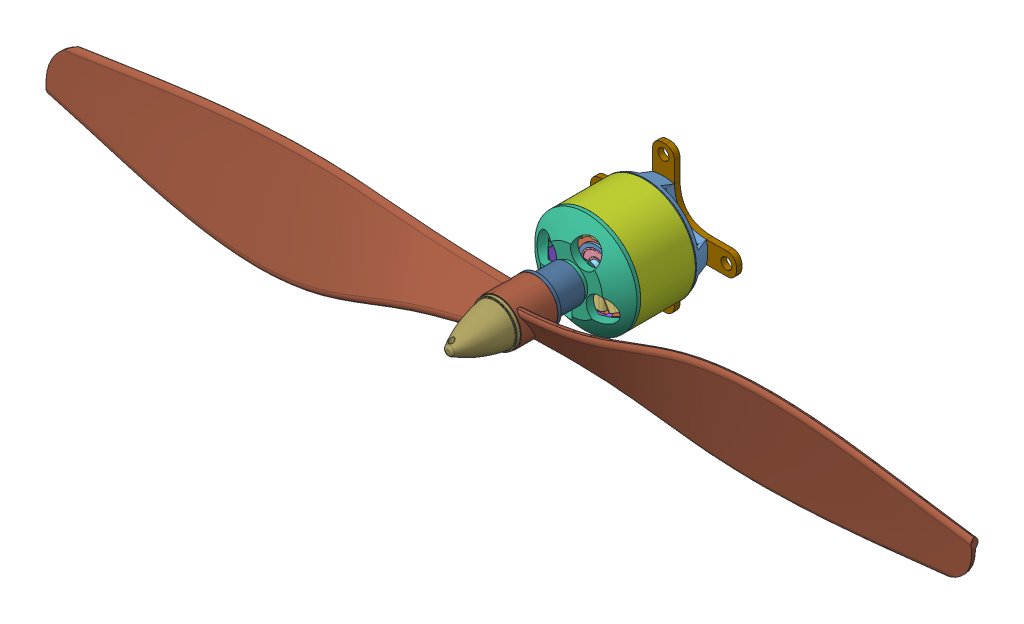
SolidWorks assembly Assem1, configuration Default. Lengths in mm.
Overall size (257.33 62.58 60.64).
40 component instances, 12 part files, 6 mates.
Components (placement in the parent):
- BLDC motor-1: BLDC motor [Default] at (-5.8676 5.6816 6.4867) size (40.24 40.24 40.73)
  - motor_stator-1: motor_stator [Default] at (4.4037 -1.9235 -1.092) size (28 28 18.85)
    - base-1: base [Default] at (10.5479 11.9817 13.9786) size (28 28 18.5)
    - armature-1: armature [Default] at (10.5479 11.9817 19.8988) x (0.999929 0.011943 0) z (0 0 1) size (22 22 12)
    - wire-1: wire [Default] at (10.4725 18.2982 25.8988) x (0.999929 0.011943 0) z (0 0 1) size (4 3.6 13.66)
    - wire-2: wire [Default] at (13.6409 17.4897 25.8988) x (0.871935 -0.489621 0) z (0 0 1) size (4 3.6 13.66)
    - wire-3: wire [Default] at (15.9805 15.2053 25.8988) x (0.510307 -0.859992 0) z (0 0 1) size (4 3.6 13.66)
    - wire-4: wire [Default] at (16.8645 12.0571 25.8988) x (0.011943 -0.999929 0) z (0 0 1) size (4 3.6 13.66)
    - wire-5: wire [Default] at (16.056 8.8887 25.8988) x (-0.489621 -0.871935 0) z (0 0 1) size (4 3.6 13.66)
    - wire-6: wire [Default] at (13.7716 6.5491 25.8988) x (-0.859992 -0.510307 0) z (0 0 1) size (4 3.6 13.66)
    - wire-7: wire [Default] at (10.6234 5.6651 25.8988) x (-0.999929 -0.011943 0) z (0 0 1) size (4 3.6 13.66)
    - wire-8: wire [Default] at (7.455 6.4736 25.8988) x (-0.871935 0.489621 0) z (0 0 1) size (4 3.6 13.66)
    - wire-9: wire [Default] at (5.1153 8.758 25.8988) x (-0.510307 0.859992 0) z (0 0 1) size (4 3.6 13.66)
    - wire-10: wire [Default] at (4.2314 11.9062 25.8988) x (-0.011943 0.999929 0) z (0 0 1) size (4 3.6 13.66)
    - wire-11: wire [Default] at (5.0399 15.0746 25.8988) x (0.489621 0.871935 0) z (0 0 1) size (4 3.6 13.66)
    - wire-12: wire [Default] at (7.3243 17.4143 25.8988) x (0.859992 0.510307 0) z (0 0 1) size (4 3.6 13.66)
    - bearing-1: bearing [Default] at (10.5479 11.9817 29.4786) x (0.999972 -0.007521 0) z (-0.007521 -0.999972 0) size (8 3 8)
    - bearing-2: bearing [Default] at (10.5479 11.9817 16.8786) x (-0.923728 -0.383049 0) z (0.383049 -0.923728 0) size (8 3 8)
  - motor_rotor-1: motor_rotor [Default] at (-28.2386 -6.9448 43.2603) x (0.999243 -0.03891 0) z (0 0 1) size (38.76 38.76 40)
    - shaft-1: shaft [Default] at (42.4959 18.6707 -31.1458) size (3 3 40)
    - rotor_part-1: rotor_part [Default] at (42.4959 18.6707 -25.1237) x (0.930002 -0.367555 0) z (0 0 1) size (28 28 11.25)
    - ring-2: ring [Default] at (42.4959 18.6707 -25.1237) x (0.836625 -0.547775 0) z (0 0 1) size (28 28 15)
    - magnet-16: magnet [Default] at (42.4959 18.6707 -24.1237) x (0.997379 0.072352 0) z (0 0 1) size (4 1.15 14)
    - magnet-17: magnet [Default] at (42.4959 18.6707 -24.1237) x (0.867216 0.497932 0) z (0 0 1) size (4 1.15 14)
    - magnet-18: magnet [Default] at (42.4959 18.6707 -24.1237) x (0.565292 0.824891 0) z (0 0 1) size (4 1.15 14)
    - magnet-19: magnet [Default] at (42.4959 18.6707 -24.1237) x (0.151405 0.988472 0) z (0 0 1) size (4 1.15 14)
    - magnet-20: magnet [Default] at (42.4959 18.6707 -24.1237) x (-0.29247 0.956275 0) z (0 0 1) size (4 1.15 14)
    - magnet-21: magnet [Default] at (42.4959 18.6707 -24.1237) x (-0.678417 0.734677 0) z (0 0 1) size (4 1.15 14)
    - magnet-22: magnet [Default] at (42.4959 18.6707 -24.1237) x (-0.929996 0.367568 0) z (0 0 1) size (4 1.15 14)
    - magnet-23: magnet [Default] at (42.4959 18.6707 -24.1237) x (-0.99738 -0.072341 0) z (0 0 1) size (4 1.15 14)
    - magnet-24: magnet [Default] at (42.4959 18.6707 -24.1237) x (-0.867221 -0.497923 0) z (0 0 1) size (4 1.15 14)
    - magnet-25: magnet [Default] at (42.4959 18.6707 -24.1237) x (-0.5653 -0.824885 0) z (0 0 1) size (4 1.15 14)
    - magnet-26: magnet [Default] at (42.4959 18.6707 -24.1237) x (-0.151415 -0.98847 0) z (0 0 1) size (4 1.15 14)
    - magnet-27: magnet [Default] at (42.4959 18.6707 -24.1237) x (0.29246 -0.956278 0) z (0 0 1) size (4 1.15 14)
    - magnet-28: magnet [Default] at (42.4959 18.6707 -24.1237) x (0.678409 -0.734684 0) z (0 0 1) size (4 1.15 14)
    - magnet-29: magnet [Default] at (42.4959 18.6707 -24.1237) x (0.929993 -0.367578 0) z (0 0 1) size (4 1.15 14)
  - clamp-1: clamp [Default] at (14.9516 10.0582 11.3866) size (40 40 1.52)
- prop adapter-1: prop adapter [Default] at (9.084 15.7398 45.8733) x (-0.929788 0.368095 0) z (0.368095 0.929788 0) size (12.49 25 12.49)
- propeller-1: propeller [Default] at (9.084 15.7398 64.5153) x (-0.03417 0.999416 0) z (-0.999416 -0.03417 0) size (53.88 22.85 255.64)
- adapter nut-1: adapter nut [Default] at (9.084 15.7398 64.5153) x (-0.970685 -0.240356 0) z (-0.240356 0.970685 0) size (12 14 12)
Mates (geometry in assembly coordinates):
- Concentric1: concentric: cylinder of assembly; cylinder of assembly; cylinder of BLDC motor-1/motor_rotor-1/shaft-1 through (9.084 15.7398 58.6012) axis (0 0 -1) radius 1.5; cylinder of prop adapter-1 through (9.084 15.7398 63.8733) axis (0 0 -1) radius 1.5
- Coincident1: coincident: plane of assembly; plane of assembly; plane of BLDC motor-1/motor_rotor-1/rotor_part-1 through (9.084 15.7398 45.8733) normal (0 0 1); plane of prop adapter-1 through (9.084 15.7398 45.8733) normal (0 0 -1)
- Concentric2: concentric: cylinder of assembly; cylinder of assembly; cylinder of prop adapter-1 through (9.084 15.7398 45.8733) axis (0 0 -1) radius 2.7441; cylinder of propeller-1 through (9.084 15.7398 54.5153) axis (0 0 1) radius 3
- Coincident2: coincident: plane of assembly; plane of assembly; plane of prop adapter-1 through (14.8897 13.4414 54.5153) normal (0 0 1); plane of propeller-1 through (9.084 15.7398 54.5153) normal (0 0 -1)
- Concentric3: concentric: cylinder of assembly; cylinder of assembly; cylinder of prop adapter-1 through (9.084 15.7398 45.8733) axis (0 0 -1) radius 2.7441; cylinder of adapter nut-1 through (9.084 15.7398 74.5153) axis (0 0 -1) radius 3
- Coincident3: coincident: plane of assembly; plane of assembly; plane of propeller-1 through (9.084 15.7398 64.5153) normal (0 0 1); plane of adapter nut-1 through (9.084 15.7398 64.5153) normal (0 0 -1)
